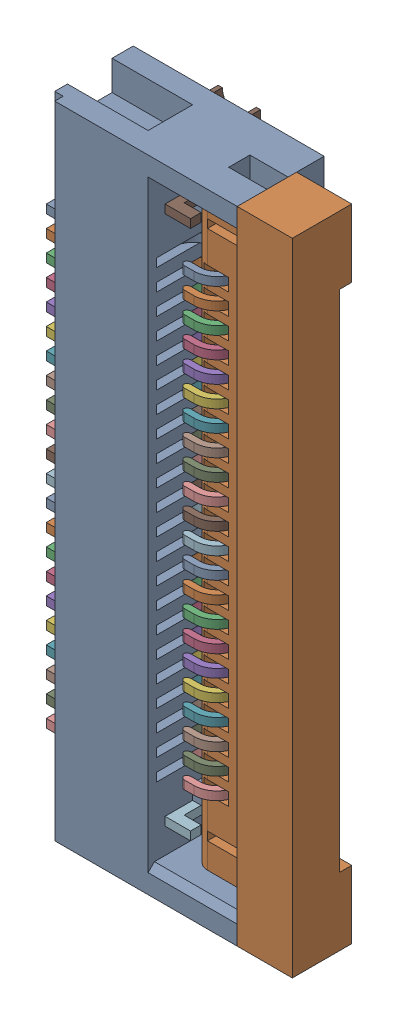
SolidWorks assembly J10, configuration Default. Lengths in mm.
Overall size (6.5 15.1 2.25).
27 component instances, 5 part files, 0 mates.
Components (placement in the parent):
- 687122149022-1: 687122149022 [Default] at (137.65 54.0001 0.7318) x (0 1 0) z (0 0 1) size (15.1 6.5 2.25)
  - 6871xx149022_Pin-1: 6871xx149022_Pin [Default] at (5.35 1.125 0.2986) x (-1 0 0) z (0 0 -1) size (0.2 4.6 2.25)
  - 6871xx149022_Pin-2: 6871xx149022_Pin [Default] at (4.85 1.125 0.2986) x (-1 0 0) z (0 0 -1) size (0.2 4.6 2.25)
  - 6871xx149022_Pin-3: 6871xx149022_Pin [Default] at (4.35 1.125 0.2986) x (-1 0 0) z (0 0 -1) size (0.2 4.6 2.25)
  - 6871xx149022_Pin-4: 6871xx149022_Pin [Default] at (3.85 1.125 0.2986) x (-1 0 0) z (0 0 -1) size (0.2 4.6 2.25)
  - 6871xx149022_Pin-5: 6871xx149022_Pin [Default] at (3.35 1.125 0.2986) x (-1 0 0) z (0 0 -1) size (0.2 4.6 2.25)
  - 6871xx149022_Pin-6: 6871xx149022_Pin [Default] at (2.85 1.125 0.2986) x (-1 0 0) z (0 0 -1) size (0.2 4.6 2.25)
  - 6871xx149022_Pin-7: 6871xx149022_Pin [Default] at (2.35 1.125 0.2986) x (-1 0 0) z (0 0 -1) size (0.2 4.6 2.25)
  - 6871xx149022_Pin-8: 6871xx149022_Pin [Default] at (1.85 1.125 0.2986) x (-1 0 0) z (0 0 -1) size (0.2 4.6 2.25)
  - 6871xx149022_Pin-9: 6871xx149022_Pin [Default] at (1.35 1.125 0.2986) x (-1 0 0) z (0 0 -1) size (0.2 4.6 2.25)
  - 6871xx149022_Pin-10: 6871xx149022_Pin [Default] at (0.85 1.125 0.2986) x (-1 0 0) z (0 0 -1) size (0.2 4.6 2.25)
  - 6871xx149022_Pin-11: 6871xx149022_Pin [Default] at (0.35 1.125 0.2986) x (-1 0 0) z (0 0 -1) size (0.2 4.6 2.25)
  - 6871xx149022_Pin-12: 6871xx149022_Pin [Default] at (-0.15 1.125 0.2986) x (-1 0 0) z (0 0 -1) size (0.2 4.6 2.25)
  - 6871xx149022_Pin-13: 6871xx149022_Pin [Default] at (-0.65 1.125 0.2986) x (-1 0 0) z (0 0 -1) size (0.2 4.6 2.25)
  - 6871xx149022_Pin-14: 6871xx149022_Pin [Default] at (-1.15 1.125 0.2986) x (-1 0 0) z (0 0 -1) size (0.2 4.6 2.25)
  - 6871xx149022_Pin-15: 6871xx149022_Pin [Default] at (-1.65 1.125 0.2986) x (-1 0 0) z (0 0 -1) size (0.2 4.6 2.25)
  - 6871xx149022_Pin-16: 6871xx149022_Pin [Default] at (-2.15 1.125 0.2986) x (-1 0 0) z (0 0 -1) size (0.2 4.6 2.25)
  - 6871xx149022_Pin-17: 6871xx149022_Pin [Default] at (-2.65 1.125 0.2986) x (-1 0 0) z (0 0 -1) size (0.2 4.6 2.25)
  - 6871xx149022_Pin-18: 6871xx149022_Pin [Default] at (-3.15 1.125 0.2986) x (-1 0 0) z (0 0 -1) size (0.2 4.6 2.25)
  - 6871xx149022_Pin-19: 6871xx149022_Pin [Default] at (-3.65 1.125 0.2986) x (-1 0 0) z (0 0 -1) size (0.2 4.6 2.25)
  - 6871xx149022_Pin-20: 6871xx149022_Pin [Default] at (-4.15 1.125 0.2986) x (-1 0 0) z (0 0 -1) size (0.2 4.6 2.25)
  - 6871xx149022_Pin-21: 6871xx149022_Pin [Default] at (-4.65 1.125 0.2986) x (-1 0 0) z (0 0 -1) size (0.2 4.6 2.25)
  - 6871xx149022_Pin-22: 6871xx149022_Pin [Default] at (-5.15 1.125 0.2986) x (-1 0 0) z (0 0 -1) size (0.2 4.6 2.25)
  - 6871xx149022_Patte-1: 6871xx149022_Patte [Default] at (6.15 0.7 -0.125) x (-1 0 0) z (0 0 1) size (1.4 3.1 1.85)
  - 6871xx149022_Patte2-1: 6871xx149022_Patte2 [Default] at (-6.35 0.7 -0.125) x (-1 0 0) z (0 0 1) size (1.4 3.1 1.85)
  - 687122149022-1: 687122149022 [Default] at origin size (15.1 4.5 2.2)
  - 687122149022_Actuator-1: 687122149022_Actuator [Default] at (0 -2.25 0.4) x (1 0 0) z (0 -1 0) size (15.1 1.4 2.9)
